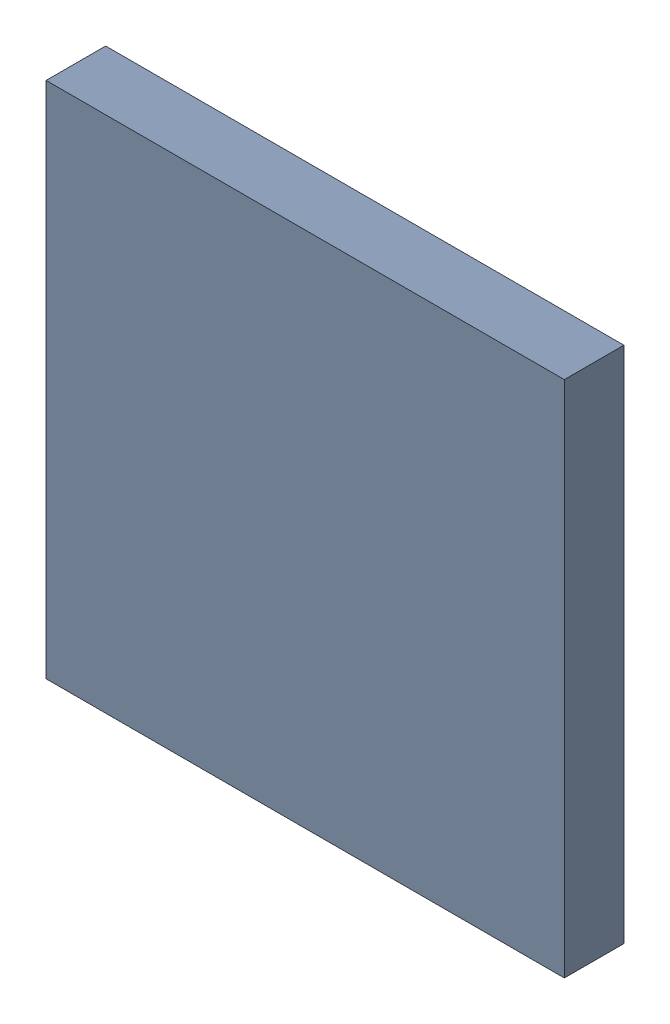
SolidWorks assembly U100_1PCB, configuration Default. Lengths in mm.
Overall size (10 10 1.15).
2 component instances, 1 part files, 0 mates.
Components (placement in the parent):
- 846485464-1: 846485464 [Default] at (106.8 113.8 0.05) size (10 10 1.15)
  - Extruded_42-1: Extruded_42 [Default] at origin size (10 10 1.15)
